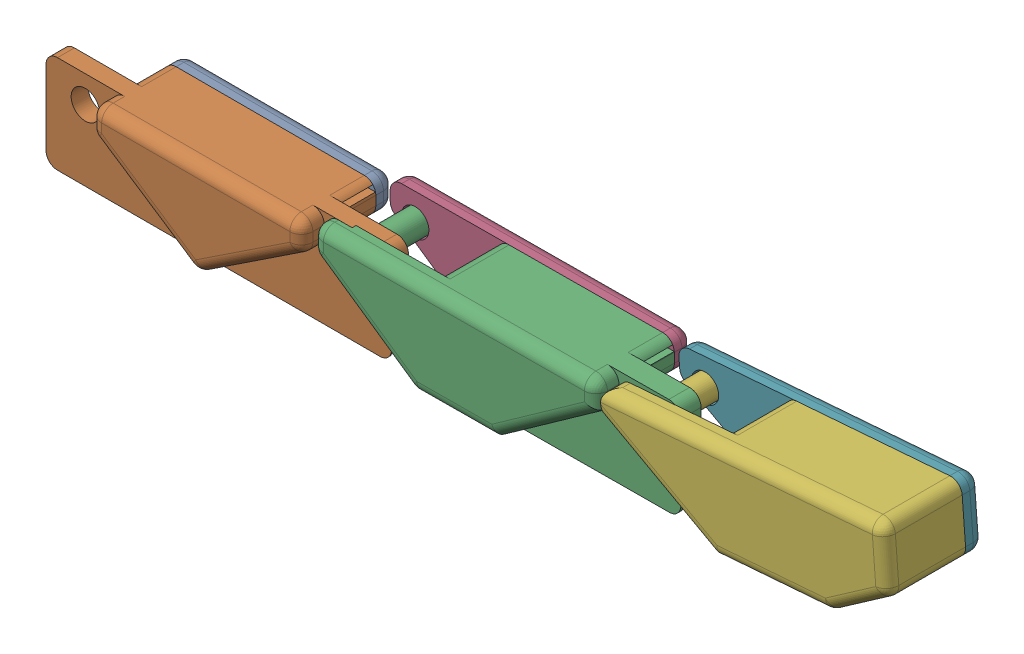
SolidWorks assembly middle finger assembly, configuration Default. Lengths in mm.
Overall size (111.99 15.58 13.71).
6 component instances, 6 part files, 10 mates.
Components (placement in the parent):
- first_knuckle_michelle_left_3-1: first_knuckle_michelle_left_3 [Default] at (-5.9832 0.413 6.8682) size (27.5 12.4 2.5)
- first_knuckle_michelle_Right_3-1: first_knuckle_michelle_Right_3 [Default] at (-2.3416 0.413 38.1464) x (0 0 1) z (-1 0 0) size (11.1 12.7 45)
- second_knuckle_michelle_R_3-1: second_knuckle_michelle_R_3 [Default] at (32.8407 0.5084 36.6384) x (0 0 1) z (-0.99998 -0.00626 0) size (11.6 12.7 45)
- second_knuckle_michelle_L_3-1: second_knuckle_michelle_L_3 [Default] at (35.595 1.4837 5.3602) x (0.99998 0.00626 0) z (0.00626 -0.99998 0) size (37 2.5 12.7)
- last_knuckle_michelleR_3-1: last_knuckle_michelleR_3 [Default] at (55.6166 0.6438 46.8148) x (0 0 1) z (-0.99694 -0.078175 0) size (11.6 12.7 37)
- last_knuckle_michelle_L_3-1: last_knuckle_michelle_L_3 [Default] at (73.8823 3.0371 5.3682) x (0.99694 0.078175 0) z (0.078175 -0.99694 0) size (37 2.5 12.7)
Mates (geometry in assembly coordinates):
- Concentric1: concentric aligned: circle of first_knuckle_michelle_left_3-1; circle of first_knuckle_michelle_Right_3-1
- Coincident1: coincident aligned: line of first_knuckle_michelle_left_3-1 through (12.4526 13.113 9.3682) axis (-1 0 0); line of first_knuckle_michelle_Right_3-1 through (12.4526 13.113 9.3682) axis (-1 0 0)
- Concentric2: concentric aligned: circle of second_knuckle_michelle_R_3-1; circle of second_knuckle_michelle_L_3-1
- Coincident2: coincident aligned: line of second_knuckle_michelle_R_3-1 through (49.805 13.3148 7.8602) axis (-0.99998 -0.00626 0); line of second_knuckle_michelle_L_3-1 through (49.805 13.3148 7.8602) axis (-0.99998 -0.00626 0)
- Concentric3: concentric anti-aligned: circle of first_knuckle_michelle_Right_3-1; circle of second_knuckle_michelle_R_3-1
- Concentric4: concentric anti-aligned: circle of last_knuckle_michelleR_3-1; circle of last_knuckle_michelle_L_3-1
- Coincident4: coincident aligned: line of last_knuckle_michelleR_3-1 through (87.2045 15.8598 7.8682) axis (-0.99694 -0.078175 0); line of last_knuckle_michelle_L_3-1 through (87.2045 15.8598 7.8682) axis (-0.99694 -0.078175 0)
- Concentric5: concentric anti-aligned: circle of second_knuckle_michelle_R_3-1; circle of last_knuckle_michelleR_3-1
- Distance3: distance = 0.508 mm: line of last_knuckle_michelleR_3-1 through (67.2658 14.2963 15.5682) axis (-0.99694 -0.078175 0); line of second_knuckle_michelle_R_3-1 through (49.805 13.3148 15.0602) axis (0.99998 0.00626 0)
- Distance4: distance = 0.508 mm: line of second_knuckle_michelle_R_3-1 through (29.8054 13.1896 15.5602) axis (-0.99998 -0.00626 0); line of first_knuckle_michelle_Right_3-1 through (12.4526 13.113 16.0682) axis (1 0 0)
